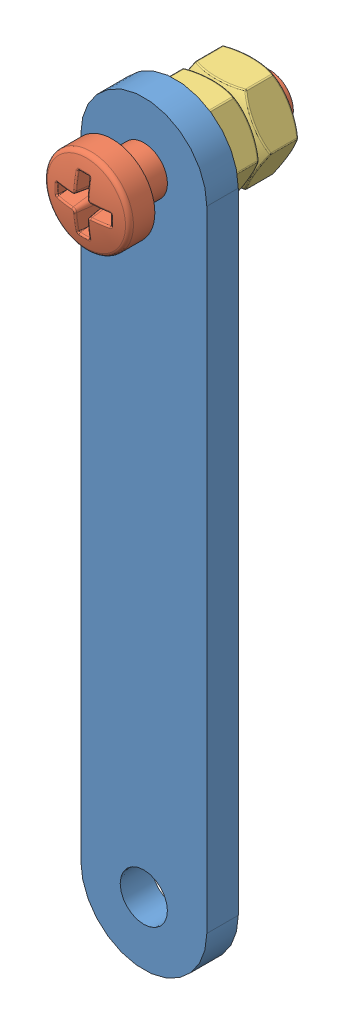
SolidWorks assembly Walking_robot_(assembled_legs_lever2), configuration Default. Lengths in mm.
Overall size (8 48 11.98).
4 component instances, 3 part files, 0 mates.
Components (placement in the parent):
- Walking_robot_(legs_lever2)-1: Walking_robot_(legs_lever2) [Default] at (-88.5069 13.1493 33.7132) size (8 48 2)
- Walking_robot_(bolt_3x10)-1: Walking_robot_(bolt_3x10) [Default] at (-88.5069 37.6493 37.7132) x (0 0 1) z (-1 0 0) size (11.98 5.4 5.4)
- Walking_robot_(nut_3)-1: Walking_robot_(nut_3) [Default] at (-88.5069 37.6493 31.2132) size (6.75 5.87 2.78)
- Walking_robot_(nut_3)-2: Walking_robot_(nut_3) [Default] at (-88.5069 37.6493 28.7132) size (6.75 5.87 2.78)
